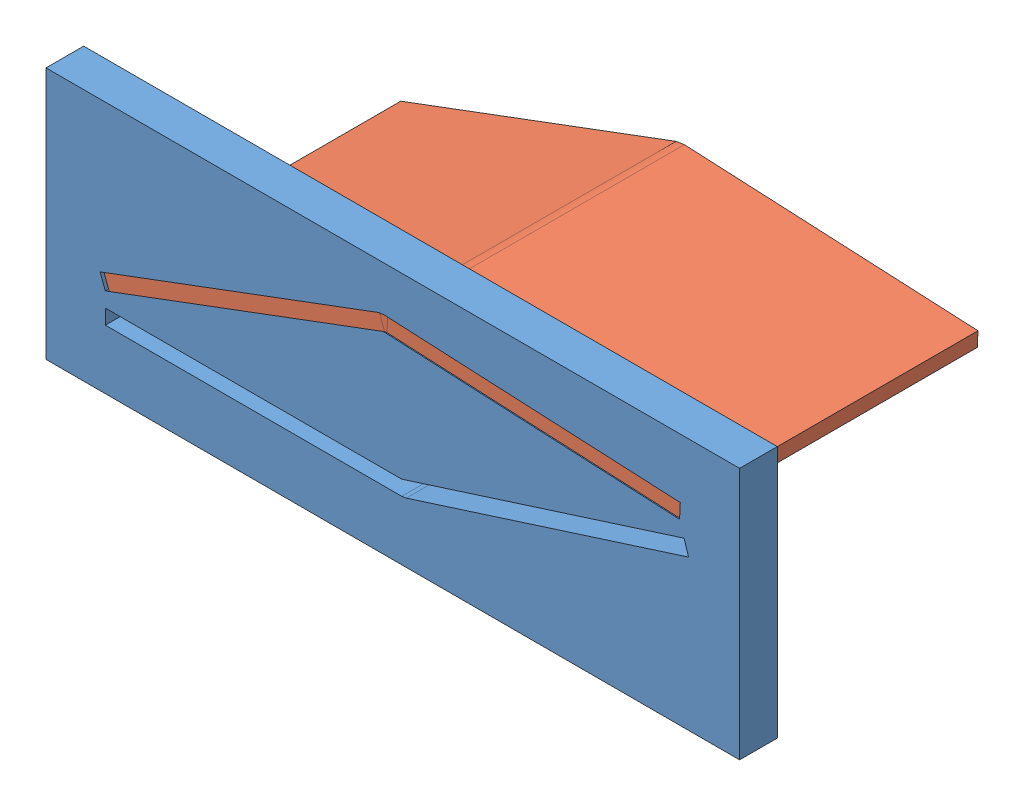
SolidWorks assembly Assem1, configuration Default. Lengths in mm.
Overall size (116.9 42.56 50).
2 component instances, 2 part files, 2 mates.
Components (placement in the parent):
- Part1-1: Part1 [Default] at (-115.2584 17.9538 45.4477) size (116.9 42.56 6.35)
- Part2-1: Part2 [Default] at (-116.6943 29.3478 26.7977) x (-0.998804 0.048897 0) z (0 0 1) size (96.43 22.17 50)
Mates (geometry in assembly coordinates):
- Coincident3: coincident anti-aligned: line of Part1-1 through (-163.7084 11.6758 51.7977) axis (0.93675 0.35 0); line of Part2-1 through (-116.6364 29.2634 51.7977) axis (-0.93675 -0.35 0)
- Coincident6: coincident aligned: plane of Part1-1 through (-115.2584 17.9538 51.7977) normal (0 0 1); plane of Part2-1 through (-66.6318 29.4 51.7977) normal (0 0 1)
